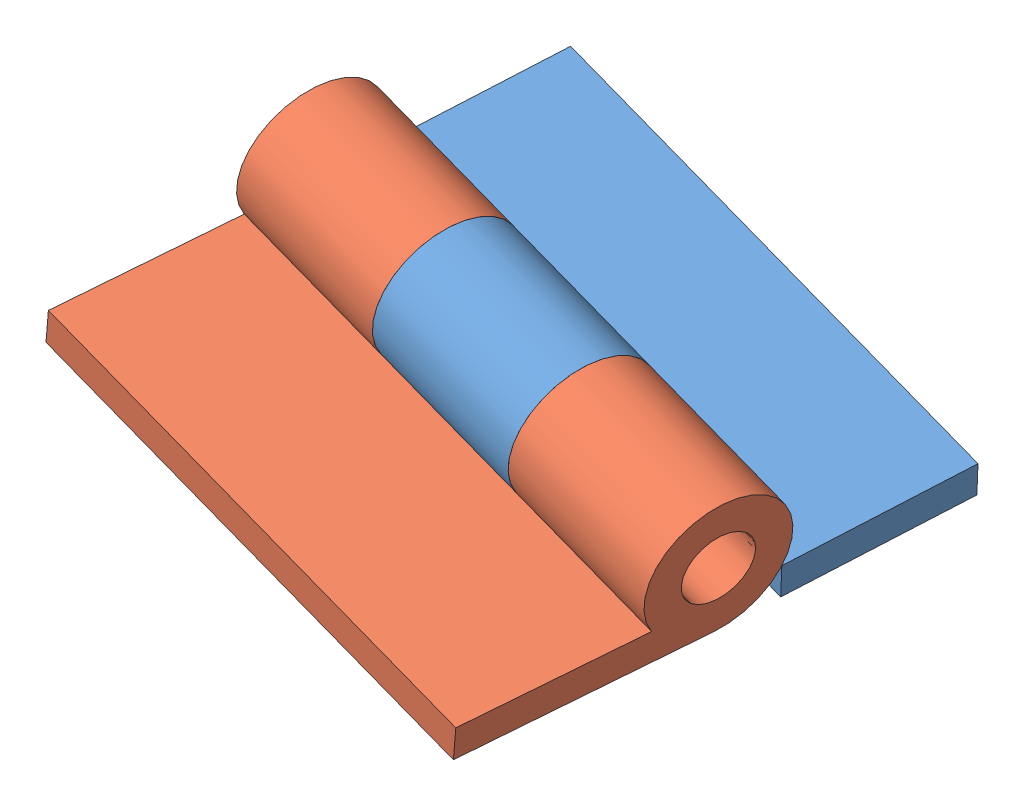
SolidWorks assembly Baugruppe_Scharnier_Heckklappe, configuration Standard. Lengths in mm.
Overall size (17.48 7.88 16.32).
2 component instances, 2 part files, 3 mates.
Components (placement in the parent):
- Scharnier_Heckklappe-1: Scharnier_Heckklappe [Standard] at (-9.8346 -0.1711 -1.6291) x (0.973146 -0.182672 0.140063) z (-0.160781 -0.103965 0.981499) size (15 4 9)
- Scharnier_Heckklappe2-1: Scharnier_Heckklappe2 [Standard] at (4.7519 -2.9171 0.5389) x (-0.973146 0.182672 -0.140063) z (0.155074 0.070589 -0.985378) size (15 4 9)
Mates (geometry in assembly coordinates):
- Deckungsgleich1: coincident: axis of Scharnier_Heckklappe-1 through (-4.6394 0.8709 -0.6677) axis (0.973146 -0.182672 0.140063); point of assembly
- Deckungsgleich2: coincident: axis of Scharnier_Heckklappe-1 through (-4.6394 0.8709 -0.6677) axis (0.973146 -0.182672 0.140063); axis of Scharnier_Heckklappe2-1 through (-4.6394 0.8709 -0.6677) axis (-0.973146 0.182672 -0.140063)
- Deckungsgleich3: coincident: plane of Scharnier_Heckklappe-1 through (-4.6394 0.8709 -0.6677) normal (-0.973146 0.182672 -0.140063); plane of Scharnier_Heckklappe2-1 through (-4.6394 0.8709 -0.6677) normal (0.973146 -0.182672 0.140063)
